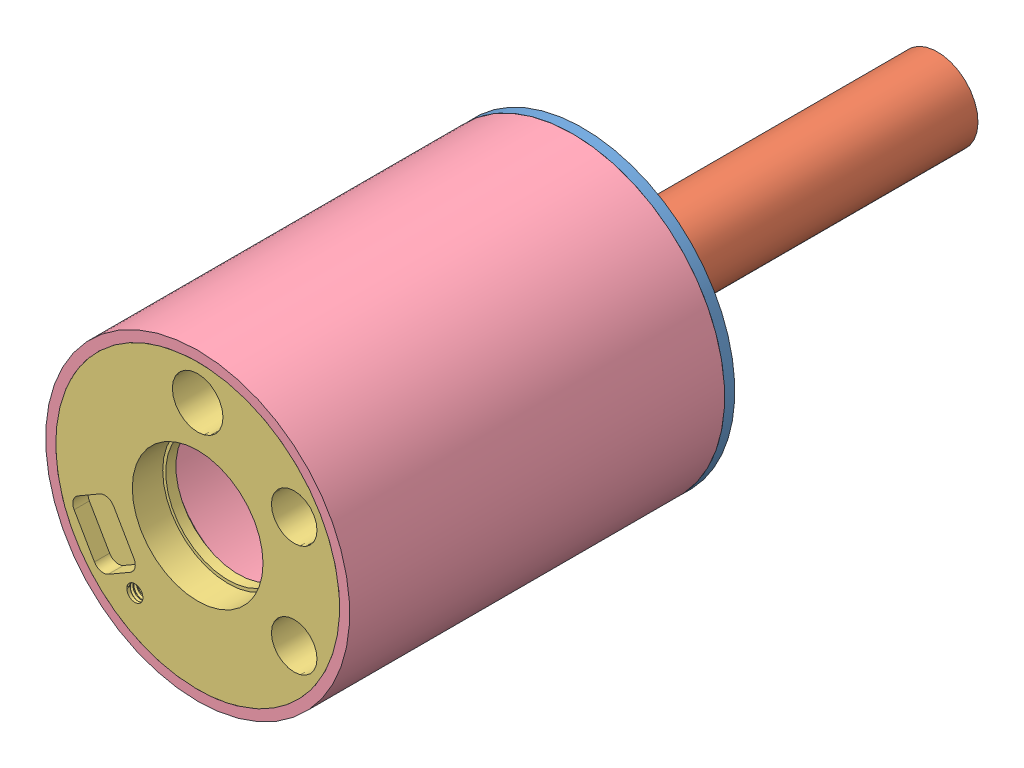
SolidWorks assembly Assem2, configuration Default. Lengths in mm.
Overall size (30 30 73.05).
5 component instances, 4 part files, 0 mates.
Components (placement in the parent):
- Cavity-1: Cavity [Default] at origin size (30 30 73.05)
  - CavityLower_20039-20-1: CavityLower_20039-20 [Default] at origin size (30 30 5)
  - CavityTail_20039-4-1: CavityTail_20039-4 [Default] at (0 0 -2) x (0.121263 0.99262 0) z (0 0 1) size (8 8 35.01)
  - CavityUpper_20039-20-1: CavityUpper_20039-20 [Default] at (0 0 31) size (28.28 28 5.05)
  - ChamberWalls_20061-13-1: ChamberWalls_20061-13 [Default] at (0 0 -1) x (-1 0 0) z (0 1 0) size (30 37 30)
